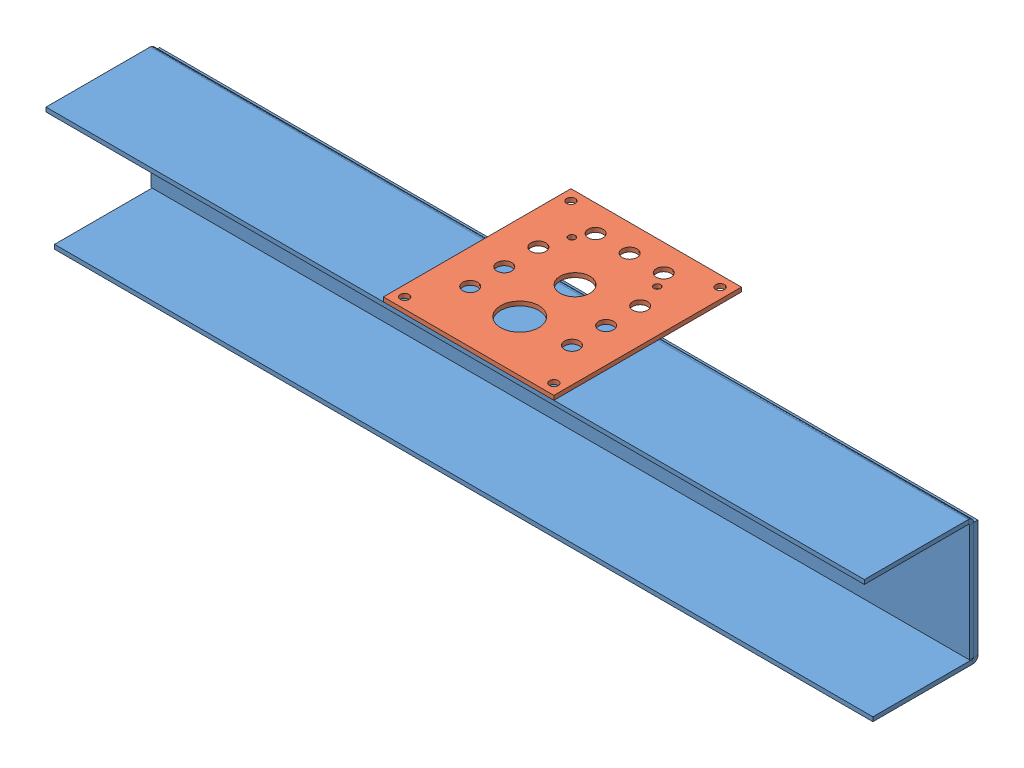
SolidWorks assembly gearbox plate with assem 2, configuration Default. Lengths in mm.
Overall size (609.6 98.07 188.83).
3 component instances, 2 part files, 2 mates.
Components (placement in the parent):
- wheel well-1: wheel well [Default] at (671.0479 -9.9353 456.7686) size (609.6 94.9 84.64)
- 3CIM Gearplate - AM14U-1: 3CIM Gearplate - AM14U [Default] at (355.0385 389.5005 649.5245) x (-0.425715 0 0.904857) z (0 -1 0) size (180.47 174.39 3.17)
  - 3CIM TB Special Shaft Plate-2: 3CIM TB Special Shaft Plate [Default] at (-39.1492 169.4106 -100.2731) x (0.425715 0.904857 0) z (0 0 1) size (127 139.7 3.17)
Mates (geometry in assembly coordinates):
- Coincident4: coincident anti-aligned: line of wheel well-1 through (513.2026 489.7736 580.0794) axis (-1 0 0); line of 3CIM Gearplate - AM14U-1/3CIM TB Special Shaft Plate-2 through (154.9125 489.7736 580.0794) axis (1 0 0)
- Coincident5: coincident anti-aligned: plane of wheel well-1 through (208.4026 489.7736 492.7669) normal (0 1 0); plane of 3CIM Gearplate - AM14U-1/3CIM TB Special Shaft Plate-2 through (154.9125 489.7736 440.3794) normal (0 -1 0)
